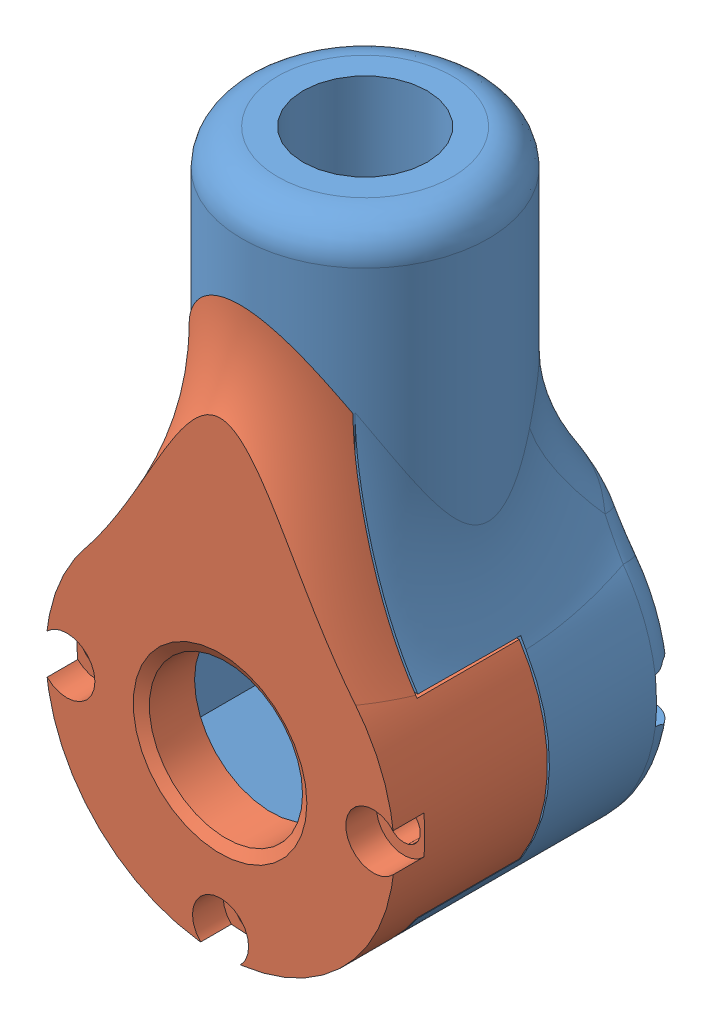
SolidWorks assembly ThreadedBarAndNutLinkageAssembled, configuration Default. Lengths in mm.
Overall size (34.1 63.1 28.83).
2 component instances, 2 part files, 3 mates.
Components (placement in the parent):
- threadedNutAndBarLinkagePart1-1: threadedNutAndBarLinkagePart1 [Default] at (27.1328 36.1413 44.3635) size (34.1 63.1 26.68)
- threadedNutAndBarLinkagePart2-1: threadedNutAndBarLinkagePart2 [Default] at (27.1328 36.1413 44.5635) size (34.1 55.31 15)
Mates (geometry in assembly coordinates):
- Concentric1: concentric anti-aligned: cylinder of threadedNutAndBarLinkagePart1-1 through (27.1328 36.1413 46.3635) axis (0 0 1) radius 7.5; cylinder of threadedNutAndBarLinkagePart2-1 through (27.1328 36.1413 79.5635) axis (0 0 -1) radius 7.5
- Parallel2: parallel anti-aligned: plane of threadedNutAndBarLinkagePart1-1 through (14.5828 36.1413 59.3635) normal (-1 0 0); plane of threadedNutAndBarLinkagePart2-1 through (14.3828 45.4451 88.6503) normal (1 0 0)
- Distance2: distance = 0.2 mm: cylinder of threadedNutAndBarLinkagePart1-1 through (27.1328 52.1913 60.3635) axis (0 -1 0) radius 12.05; cylinder of threadedNutAndBarLinkagePart2-1 through (27.1328 66.4484 60.5635) axis (0 1 0) radius 12.05
